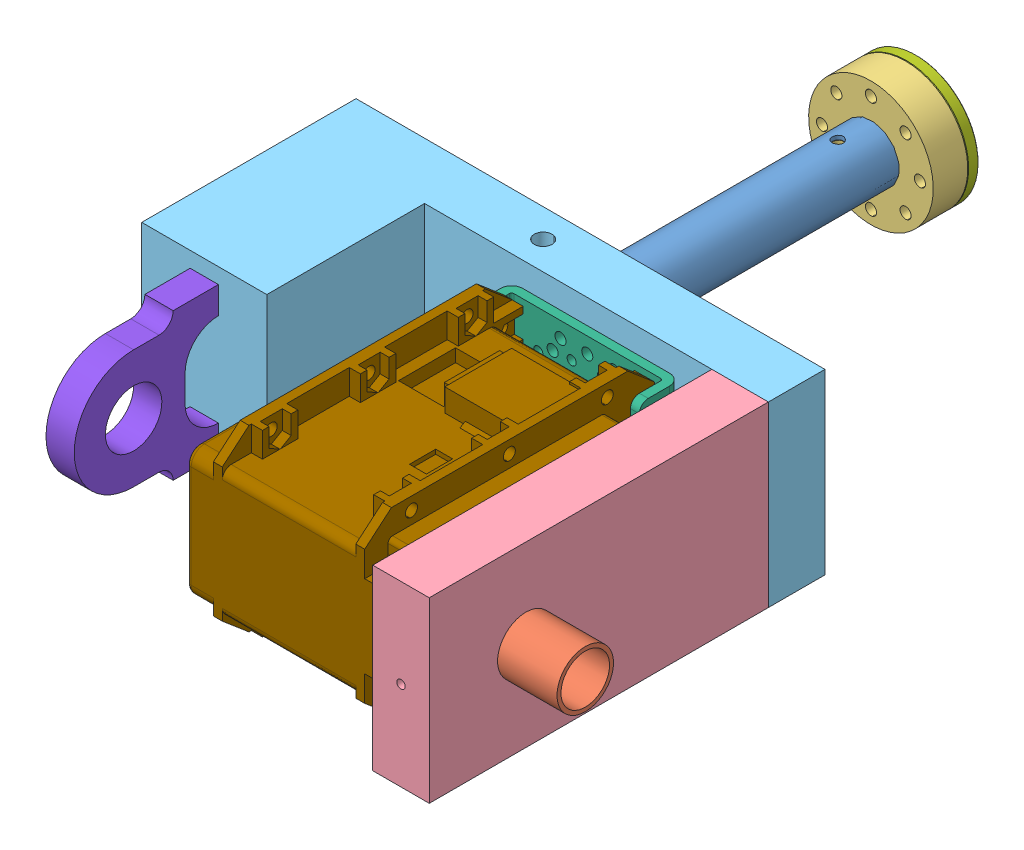
SolidWorks assembly Link2, configuration Default. Lengths in mm.
Overall size (118.7 41.6 167.45).
9 component instances, 9 part files, 24 mates.
Components (placement in the parent):
- at-06_Motor1-1: at-06_Motor1 [Default] at (-21.5651 99.4213 109.8204) size (12.7 12.7 80)
- at-06-Motor2-2_v2-1: at-06-Motor2-2_v2 [Default] at (22.6949 99.4213 244.3204) x (0 -1 0) z (1 0 0) size (12.7 12.7 26.05)
- HN05-N101_to_at-06_attachment_6_27-1: HN05-N101_to_at-06_attachment_6_27 [Default] at (-21.5651 99.4213 109.8204) x (-1 0 0) z (0 -1 0) size (28 26.75 28)
- Motor2Back-1: Motor2Back [Default] at (35.3949 91.3901 189.8204) x (-1 0 0) z (0 1 0) size (12.7 76.2 40)
- Motor2Bottom-1: Motor2Bottom [Default] at (35.3949 91.3901 187.9368) x (-1 0 0) z (0 1 0) size (105.35 48.15 40)
- FR05-S101-1: FR05-S101 [Default] at (-3.3051 99.4213 189.8204) x (0 1 0) z (1 0 0) size (36 9.31 38.02)
- HN05-N101-1: HN05-N101 [Default] at (-21.5651 99.4213 99.5704) x (1 0 0) z (0 -1 0) size (28 5.3 28)
- PillowBlock-1: PillowBlock [Default] at (-52.7301 99.4213 244.3204) x (0 -1 0) z (-1 0 0) size (33.02 32.38 6.35)
- EX-106+-1: EX-106+ [Default] at (-3.3051 99.4213 244.3204) x (0 -1 0) z (-1 0 0) size (40.2 65.92 50.9)
Mates (geometry in assembly coordinates):
- Concentric1: concentric aligned: circle of Motor2Back-1; circle of Motor2Bottom-1
- Concentric2: concentric aligned: circle of Motor2Back-1; circle of Motor2Bottom-1
- Coincident1: coincident anti-aligned: plane of Motor2Back-1 through (35.3949 91.3901 189.8204) normal (0 0 -1); plane of Motor2Bottom-1 through (-69.9551 119.4213 189.8204) normal (0 0 1)
- Concentric3: concentric aligned: circle of Motor2Bottom-1; circle of FR05-S101-1
- Concentric4: concentric aligned: circle of Motor2Bottom-1; circle of FR05-S101-1
- Coincident2: coincident anti-aligned: plane of Motor2Bottom-1 through (-69.9551 119.4213 189.8204) normal (0 0 1); plane of FR05-S101-1 through (13.1949 113.9213 189.8204) normal (0 0 -1)
- Concentric5: concentric aligned: circle of FR05-S101-1; circle of EX-106+-1
- Concentric6: concentric aligned: circle of FR05-S101-1; circle of EX-106+-1
- Coincident3: coincident anti-aligned: plane of FR05-S101-1 through (-20.3051 113.9213 192.3204) normal (1 0 0); plane of EX-106+-1 through (-20.3051 99.4213 244.3204) normal (-1 0 0)
- Concentric7: concentric anti-aligned: circle of Motor2Bottom-1; circle of PillowBlock-1
- Concentric8: concentric anti-aligned: circle of Motor2Bottom-1; circle of PillowBlock-1
- Coincident4: coincident anti-aligned: plane of Motor2Bottom-1 through (35.3949 91.3901 225.2704) normal (0 0 1); plane of PillowBlock-1 through (-59.0801 88.9819 225.2704) normal (0 0 -1)
- Concentric9: concentric aligned: circle of HN05-N101_to_at-06_attachment_6_27-1; circle of HN05-N101-1
- Concentric10: concentric anti-aligned: circle of HN05-N101_to_at-06_attachment_6_27-1; circle of HN05-N101-1
- Coincident5: coincident anti-aligned: plane of HN05-N101_to_at-06_attachment_6_27-1 through (-21.5651 99.4213 102.0704) normal (0 0 -1); plane of HN05-N101-1 through (-21.5651 99.4213 102.0704) normal (0 0 1)
- Concentric15: concentric aligned: circle of at-06_Motor1-1; circle of HN05-N101_to_at-06_attachment_6_27-1
- Parallel4: parallel anti-aligned: cylinder of at-06_Motor1-1 through (-21.5651 61.3213 117.3204) axis (0 1 0) radius 1.25; cylinder of HN05-N101_to_at-06_attachment_6_27-1 through (-21.5651 113.4213 117.3204) axis (0 -1 0) radius 1.25
- Coincident8: coincident anti-aligned: plane of at-06_Motor1-1 through (-21.5651 99.4213 109.8204) normal (0 0 -1); plane of HN05-N101_to_at-06_attachment_6_27-1 through (-21.5651 99.4213 109.8204) normal (0 0 1)
- Concentric16: concentric aligned: circle of at-06_Motor1-1; circle of Motor2Bottom-1
- Parallel6: parallel aligned: cylinder of at-06_Motor1-1 through (-21.5651 61.3213 183.4704) axis (0 1 0) radius 2; cylinder of Motor2Bottom-1 through (-21.5651 119.4213 183.4704) axis (0 1 0) radius 2
- Coincident9: coincident aligned: circle of at-06_Motor1-1; plane of Motor2Bottom-1 through (-69.9551 119.4213 189.8204) normal (0 0 1)
- Concentric17: concentric anti-aligned: circle of at-06-Motor2-2_v2-1; circle of Motor2Back-1
- Parallel7: parallel anti-aligned: cylinder of at-06-Motor2-2_v2-1 through (29.0449 99.4213 282.4204) axis (0 0 -1) radius 1.25; cylinder of Motor2Back-1 through (29.0449 99.4213 236.0204) axis (0 0 1) radius 0.95
- Coincident10: coincident aligned: plane of at-06-Motor2-2_v2-1 through (22.6949 99.4213 244.3204) normal (-1 0 0); plane of Motor2Back-1 through (22.6949 119.4213 266.0204) normal (-1 0 0)
